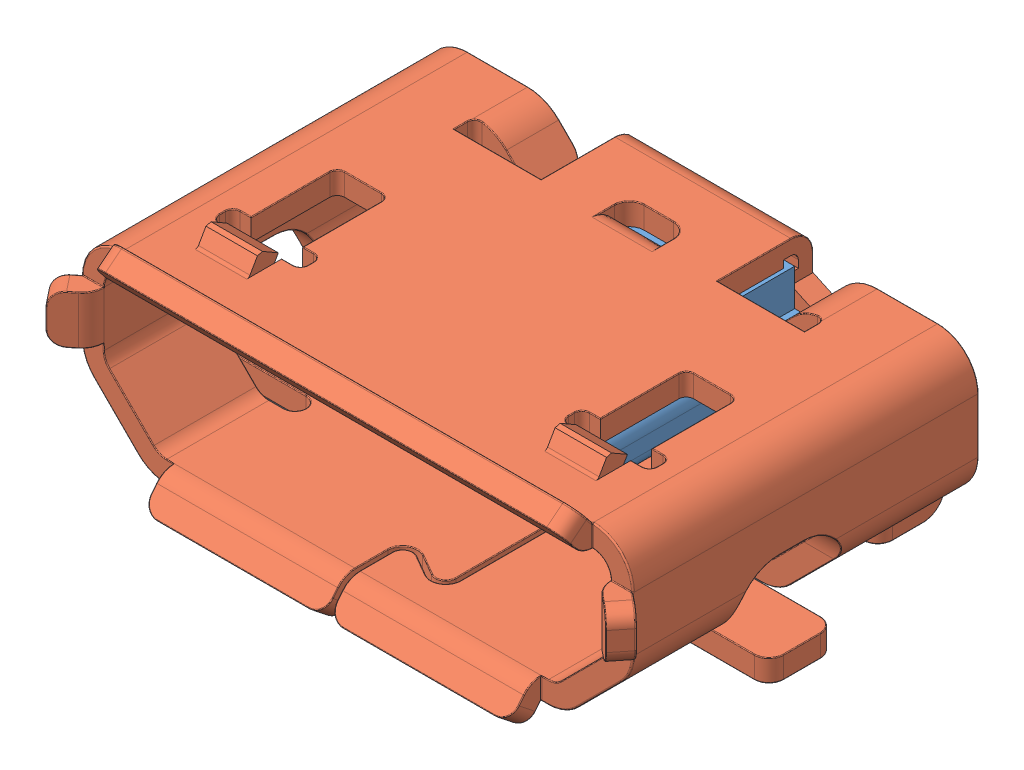
SolidWorks assembly micro USB, configuration Défaut. Lengths in mm.
Overall size (7.99 2.94 5.43).
2 component instances, 2 part files, 0 mates.
Components (placement in the parent):
- micro usb02-1: micro usb02 [Défaut] at (-14.4796 6.4719 -20.7085) size (6.9 2.16 4.2)
- micro USB-1: micro USB [Défaut] at (-14.4796 6.4719 -16.0085) size (7.99 2.94 5.43)
